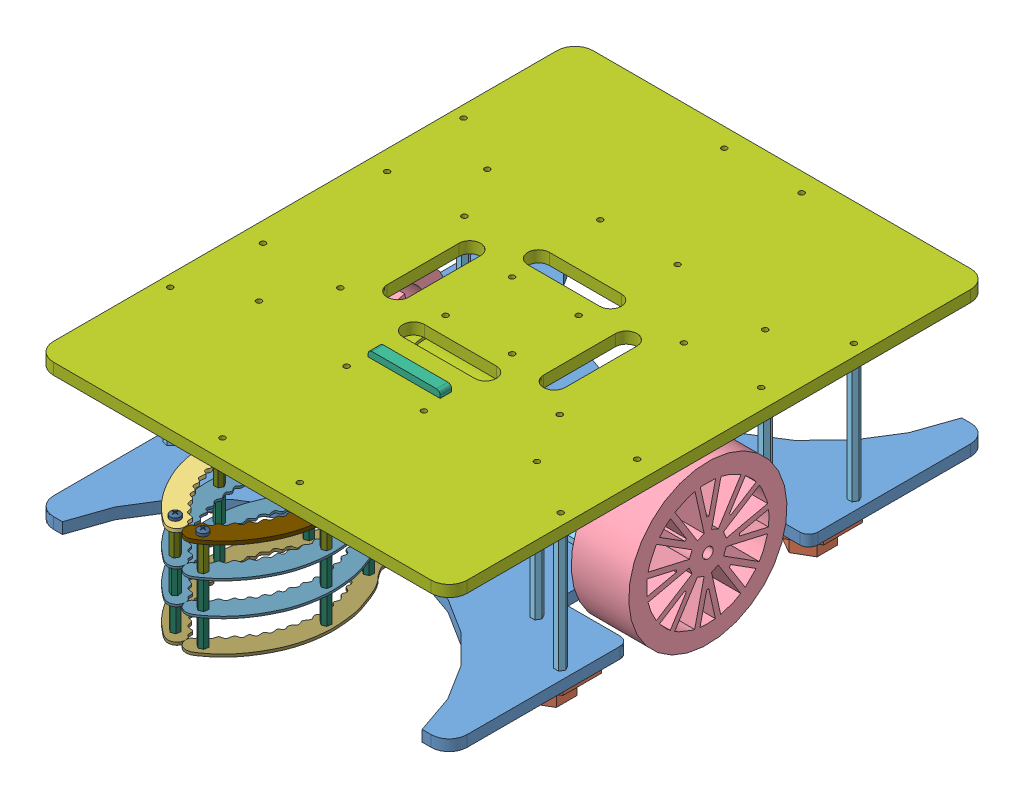
SolidWorks assembly 小车2.0(First Review), configuration Default. Lengths in mm.
Overall size (314.63 161.96 343.93).
98 component instances, 25 part files, 63 mates.
Components (placement in the parent):
- Final Project底板-1: Final Project底板 [Default] at (93.3392 132.9581 90.5224) size (230 6.18 300)
- 滚珠-1: 滚珠 [Default] at (103.3123 152.3308 292.8973) x (0 0 -1) z (0 -1 0) size (43.11 37.34 23.7)
  - 滚珠安装架-1: 滚珠安装架 [Default] at (13.0967 20.7229 19.3727) size (43.11 37.34 17.78)
  - 滚珠球-1: 滚珠球 [Default] at (13.0967 20.7229 37.7877) x (0.980181 0.176565 -0.08983) z (0.185914 -0.976466 0.109313) size (8.89 8.89 8.89)
- 滚珠-2: 滚珠 [Default] at (102.3317 152.3308 123.4025) x (0.866025 0 -0.5) z (0 -1 0) size (43.11 37.34 23.7)
  - 滚珠安装架-1: 滚珠安装架 [Default] at (13.0967 20.7229 19.3727) size (43.11 37.34 17.78)
  - 滚珠球-1: 滚珠球 [Default] at (13.0967 20.7229 37.7877) x (0.980181 0.176565 -0.08983) z (0.185914 -0.976466 0.109313) size (8.89 8.89 8.89)
- 滚珠-3: 滚珠 [Default] at (289.0923 152.3308 147.8973) x (0 0 -1) z (0 -1 0) size (43.11 37.34 23.7)
  - 滚珠安装架-1: 滚珠安装架 [Default] at (13.0967 20.7229 19.3727) size (43.11 37.34 17.78)
  - 滚珠球-1: 滚珠球 [Default] at (13.0967 20.7229 37.7877) x (0.980181 0.176565 -0.08983) z (0.185914 -0.976466 0.109313) size (8.89 8.89 8.89)
- 滚珠-4: 滚珠 [Default] at (288.1117 152.3308 268.4025) x (0.866025 0 -0.5) z (0 -1 0) size (43.11 37.34 23.7)
  - 滚珠安装架-1: 滚珠安装架 [Default] at (13.0967 20.7229 19.3727) size (43.11 37.34 17.78)
  - 滚珠球-1: 滚珠球 [Default] at (13.0967 20.7229 37.7877) x (0.980181 0.176565 -0.08983) z (0.185914 -0.976466 0.109313) size (8.89 8.89 8.89)
- Motor to Wheel-1: Motor to Wheel [Default] at (328.9008 -32.1069 184.0203) x (0.155875 -0.109432 -0.981696) z (0.856774 0.509569 0.079237) size (127.19 130.48 130.09)
  - Wheel-1: Wheel [Default] at (-48.6444 171.6674 66.3367) x (0.769981 -0.482848 -0.417117) z (0.155875 -0.491571 0.856774) size (88 88 32)
  - Motor Mount-1: Motor Mount [Default] at (-46.2771 169.9687 66.283) x (-0.981696 -0.173188 0.079237) z (-0.155875 0.491571 -0.856774) size (38 27 30)
  - DShaftAdaptor_FinalProject-1: DShaftAdaptor_FinalProject [默认] at (-47.3974 167.7348 73.1909) x (0.357457 -0.780517 -0.512852) z (-0.92083 -0.3862 -0.054052) size (12 18.01 13.86)
  - DC_FinalProject-1: DC_FinalProject [默认] at (-61.014 214.2892 6.2529) x (0.981685 0.173278 -0.079184) z (0.109535 -0.853424 -0.509577) size (37 94.36 37)
- Motor to Wheel-2: Motor to Wheel [Default] at (104.9496 -32.1069 230.581) x (-0.155875 -0.109432 0.981696) z (-0.856774 0.509569 -0.079237) size (127.19 130.48 130.09)
  - Wheel-1: Wheel [Default] at (-48.6444 171.6674 66.3367) x (0.769981 -0.482848 -0.417117) z (0.155875 -0.491571 0.856774) size (88 88 32)
  - Motor Mount-1: Motor Mount [Default] at (-46.2771 169.9687 66.283) x (-0.981696 -0.173188 0.079237) z (-0.155875 0.491571 -0.856774) size (38 27 30)
  - DShaftAdaptor_FinalProject-1: DShaftAdaptor_FinalProject [默认] at (-47.3974 167.7348 73.1909) x (0.357457 -0.780517 -0.512852) z (-0.92083 -0.3862 -0.054052) size (12 18.01 13.86)
  - DC_FinalProject-1: DC_FinalProject [默认] at (-61.014 214.2892 6.2529) x (0.981685 0.173278 -0.079184) z (0.109535 -0.853424 -0.509577) size (37 94.36 37)
- CLAW-1: CLAW [默认] at (273.9252 167.8265 279.8987) x (0 -1 0) z (-1 0 0) size (68 134.79 94.66)
  - 支架1-1: 支架1 [默认] at (-30.3115 13.402 28.5) size (50 26 57)
  - M3X11双通铜柱-1: M3X11双通铜柱 [默认] at (-17.3115 9.067 31.75) x (0 0 1) z (-1 0 0) size (5 4.33 11)
  - GB818-M3X6-ZN-4.8-1: GB818-M3X6-ZN-4.8 [默认] at (-24.3115 6.902 33) x (0 0 1) z (-1 0 0) size (5.68 5.86 8.4)
  - M3X11双通铜柱-2: M3X11双通铜柱 [默认] at (-17.3115 -0.933 31.75) x (0 0 1) z (-1 0 0) size (5 4.33 11)
  - GB818-M3X6-ZN-4.8-2: GB818-M3X6-ZN-4.8 [默认] at (-24.3115 -3.098 33) x (0 0 1) z (-1 0 0) size (5.68 5.86 8.4)
  - M3X11双通铜柱-3: M3X11双通铜柱 [默认] at (-17.3115 9.067 79.75) x (0 0 1) z (-1 0 0) size (5 4.33 11)
  - M3X11双通铜柱-4: M3X11双通铜柱 [默认] at (-17.3115 -0.933 79.75) x (0 0 1) z (-1 0 0) size (5 4.33 11)
  - GB818-M3X6-ZN-4.8-3: GB818-M3X6-ZN-4.8 [默认] at (-24.3115 -3.098 81) x (0 0 1) z (-1 0 0) size (5.68 5.86 8.4)
  - GB818-M3X6-ZN-4.8-4: GB818-M3X6-ZN-4.8 [默认] at (-24.3115 6.902 81) x (0 0 1) z (-1 0 0) size (5.68 5.86 8.4)
  - GB818-M3X10-ZN-4.8-1: GB818-M3X10-ZN-4.8 [默认] at (27.6885 1.902 43) x (0 0 1) z (-1 0 0) size (5.68 5.86 12.4)
  - 底部长支架-1: 底部长支架 [默认] at (19.6885 2.0479 43.1669) x (0 -0.990726 -0.135879) z (1 0 0) size (118.75 37.12 1.5)
  - GB6170-M3（自锁）-1: GB6170-M3（自锁） [默认] at (23.5885 1.902 43) x (0 0.843024 -0.537877) z (1 0 0) size (5.54 6.35 3.9)
  - 底部长支架-2: 底部长支架 [默认] at (21.1885 2.0535 66.8382) x (0 -0.994786 0.101989) z (-1 0 0) size (118.75 37.12 1.5)
  - GB818-M3X10-ZN-4.8-2: GB818-M3X10-ZN-4.8 [默认] at (27.6885 1.902 67) x (0 0.048732 -0.998812) z (-1 0 0) size (5.68 5.86 12.4)
  - GB6170-M3（自锁）-2: GB6170-M3（自锁） [默认] at (23.5885 1.902 67) x (0 0.843024 -0.537877) z (1 0 0) size (5.54 6.35 3.9)
  - 装配体3-1: 装配体3 [默认] at (15.0497 28.6742 176.351) x (0 -0.994786 0.101989) z (0 -0.101989 -0.994786) size (98.03 52.4 32.23)
    - 短支架-1: 短支架 [默认] at (-8.1796 12.3612 103.8864) size (98.03 1.2 32.23)
    - M3X17+6铜柱-1: M3X17+6铜柱 [默认] at (-9.1857 -4.6388 105.7687) x (-0.247063 0 -0.969) z (0 1 0) size (5 4.33 23)
    - M3X17+6铜柱-2: M3X17+6铜柱 [默认] at (-43.3235 -4.6388 88.3304) x (-0.247063 0 -0.969) z (0 1 0) size (5 4.33 23)
    - M3X17+6铜柱-3: M3X17+6铜柱 [默认] at (-91.3824 -4.6388 105.0913) x (-0.247063 0 -0.969) z (0 1 0) size (5 4.33 23)
    - M3X17+6铜柱-4: M3X17+6铜柱 [默认] at (-42.7844 13.5612 84.4192) x (1 0 0) z (0 1 0) size (5 4.33 23)
    - M3X17+6铜柱-5: M3X17+6铜柱 [默认] at (-8.6466 13.5612 101.8575) x (1 0 0) z (0 1 0) size (5 4.33 23)
    - M3X17+6铜柱-6: M3X17+6铜柱 [默认] at (-90.8433 13.5612 101.1801) x (1 0 0) z (0 1 0) size (5 4.33 23)
    - 短支架-2: 短支架 [默认] at (-8.1796 30.5612 103.8864) size (98.03 1.2 32.23)
    - M3X16双通铜柱-1: M3X16双通铜柱 [默认] at (-87.3627 47.7612 102.2163) x (-0.837169 0 -0.546944) z (0 -1 0) size (5 4.33 16)
    - M3X16双通铜柱-2: M3X16双通铜柱 [默认] at (-39.3038 47.7612 85.4554) x (-0.837169 0 -0.546944) z (0 -1 0) size (5 4.33 16)
    - M3X16双通铜柱-3: M3X16双通铜柱 [默认] at (-5.1659 47.7612 102.8937) x (-0.837169 0 -0.546944) z (0 -1 0) size (5 4.33 16)
  - GB818-M3X6-ZN-4.8-5: GB818-M3X6-ZN-4.8 [默认] at (15.1885 61.1614 85.9822) x (0 0 -1) z (1 0 0) size (5.68 5.86 8.4)
  - GB818-M3X6-ZN-4.8-6: GB818-M3X6-ZN-4.8 [默认] at (15.1885 107.2603 64.4072) x (0 0 -1) z (1 0 0) size (5.68 5.86 8.4)
  - GB818-M3X6-ZN-4.8-7: GB818-M3X6-ZN-4.8 [默认] at (15.1885 25.4231 72.1164) x (0 0 -1) z (1 0 0) size (5.68 5.86 8.4)
  - 装配体4-1: 装配体4 [默认] at (-2.8438 34.6565 -65.0628) x (0 -0.990726 -0.135879) z (0 -0.135879 0.990726) size (98.03 52.4 32.23)
    - 短支架-1: 短支架 [默认] at (-5.8923 4.3323 103.8864) size (98.03 1.2 32.23)
    - M3X17+6铜柱-1: M3X17+6铜柱 [默认] at (-88.556 22.5323 105.5102) x (1 0 0) z (0 -1 0) size (5 4.33 23)
    - M3X16双通铜柱-1: M3X16双通铜柱 [默认] at (-40.4971 -29.8677 84.4192) x (1 0 0) z (0 1 0) size (5 4.33 16)
    - M3X17+6铜柱-2: M3X17+6铜柱 [默认] at (-40.4971 22.5323 88.7493) x (1 0 0) z (0 -1 0) size (5 4.33 23)
    - M3X17+6铜柱-3: M3X17+6铜柱 [默认] at (-6.3593 22.5323 106.1877) x (1 0 0) z (0 -1 0) size (5 4.33 23)
    - M3X17+6铜柱-4: M3X17+6铜柱 [默认] at (-6.3593 4.3323 106.1877) x (1 0 0) z (0 -1 0) size (5 4.33 23)
    - M3X17+6铜柱-5: M3X17+6铜柱 [默认] at (-40.4971 4.3323 88.7493) x (1 0 0) z (0 -1 0) size (5 4.33 23)
    - M3X17+6铜柱-6: M3X17+6铜柱 [默认] at (-88.556 4.3323 105.5102) x (1 0 0) z (0 -1 0) size (5 4.33 23)
    - 短支架-2: 短支架 [默认] at (-5.8923 -13.8677 103.8864) size (98.03 1.2 32.23)
    - M3X16双通铜柱-2: M3X16双通铜柱 [默认] at (-88.556 -29.8677 101.1801) x (1 0 0) z (0 1 0) size (5 4.33 16)
    - M3X16双通铜柱-3: M3X16双通铜柱 [默认] at (-6.3593 -29.8677 101.8575) x (1 0 0) z (0 1 0) size (5 4.33 16)
  - GB818-M3X6-ZN-4.8-8: GB818-M3X6-ZN-4.8 [默认] at (15.1885 25.584 38.6892) x (0 0 -1) z (1 0 0) size (5.68 5.86 8.4)
  - GB818-M3X6-ZN-4.8-9: GB818-M3X6-ZN-4.8 [默认] at (15.1885 61.7747 26.0512) x (0 0 -1) z (1 0 0) size (5.68 5.86 8.4)
  - GB818-M3X6-ZN-4.8-10: GB818-M3X6-ZN-4.8 [默认] at (15.1885 107.1104 49.1869) x (0 0 -1) z (1 0 0) size (5.68 5.86 8.4)
  - GB818-M3X12-ZN-4.8-1: GB818-M3X12-ZN-4.8 [默认] at (-40.3115 1.902 43) x (0 0 -1) z (1 0 0) size (5.68 5.86 14.4)
  - 左边长支架-1: 左边长支架 [默认] at (-34.7115 1.9971 43.5105) x (0 -0.990726 -0.135879) z (0 -0.135879 0.990726) size (129.58 2 47.14)
  - GB6170-M3（自锁）-3: GB6170-M3（自锁） [默认] at (-37.1115 1.902 43) x (0 0 1) z (-1 0 0) size (5.54 6.35 3.9)
  - GB818-M3X6-ZN-4.8-11: GB818-M3X6-ZN-4.8 [默认] at (-28.7115 25.584 38.6892) x (0 0 1) z (-1 0 0) size (5.68 5.86 8.4)
  - GB818-M3X6-ZN-4.8-12: GB818-M3X6-ZN-4.8 [默认] at (-28.7115 61.7747 26.0512) x (0 0 1) z (-1 0 0) size (5.68 5.86 8.4)
  - GB818-M3X6-ZN-4.8-13: GB818-M3X6-ZN-4.8 [默认] at (-28.7115 107.1104 49.1869) x (0 0 1) z (-1 0 0) size (5.68 5.86 8.4)
  - 小舵机-1: 小舵机 [默认] at (-25.3115 1.902 77) x (0 0 -1) z (0 1 0) size (57.5 45 20)
  - GB818-M3X6-ZN-4.8-14: GB818-M3X6-ZN-4.8 [默认] at (-20.3115 -3.098 81) x (0 0 -1) z (1 0 0) size (5.68 5.86 8.4)
  - GB818-M3X6-ZN-4.8-15: GB818-M3X6-ZN-4.8 [默认] at (-20.3115 6.902 81) x (0 0 -1) z (1 0 0) size (5.68 5.86 8.4)
  - GB818-M3X6-ZN-4.8-16: GB818-M3X6-ZN-4.8 [默认] at (-20.3115 6.902 33) x (0 0 -1) z (1 0 0) size (5.68 5.86 8.4)
  - GB818-M3X6-ZN-4.8-17: GB818-M3X6-ZN-4.8 [默认] at (-20.3115 -3.098 33) x (0 0 -1) z (1 0 0) size (5.68 5.86 8.4)
  - 金属主舵盘-1: 金属主舵盘 [默认] at (-32.7115 1.902 67) x (0 0.544938 -0.838476) z (0 -0.838476 -0.544938) size (20 4.5 20)
  - 右边长支架-1: 右边长支架 [默认] at (-32.7115 2.0165 67.0256) x (0 -0.994786 0.101989) z (0 -0.101989 -0.994786) size (129.29 2 48.17)
  - GB818-M3X6-ZN-4.8-18: GB818-M3X6-ZN-4.8 [默认] at (-28.7115 107.2603 64.4072) x (0 0 1) z (-1 0 0) size (5.68 5.86 8.4)
  - GB818-M3X6-ZN-4.8-19: GB818-M3X6-ZN-4.8 [默认] at (-28.7115 61.1614 85.9822) x (0 0 1) z (-1 0 0) size (5.68 5.86 8.4)
  - GB818-M3X6-ZN-4.8-20: GB818-M3X6-ZN-4.8 [默认] at (-28.7115 25.4231 72.1164) x (0 0 1) z (-1 0 0) size (5.68 5.86 8.4)
  - GB818-M3X6-ZN-4.8-21: GB818-M3X6-ZN-4.8 [默认] at (-26.7115 1.902 67) x (0 0 1) z (-1 0 0) size (5.68 5.86 8.4)
  - GB818-M3X5-ZN-4.8-1: GB818-M3X5-ZN-4.8 [默认] at (-29.7115 1.5867 73.9644) x (0 0 1) z (-1 0 0) size (5.68 5.86 7.4)
  - GB818-M3X5-ZN-4.8-2: GB818-M3X5-ZN-4.8 [默认] at (-29.7115 2.0134 60.0146) x (0 0 1) z (-1 0 0) size (5.68 5.86 7.4)
- erSupport-1: erSupport [Default] at (108.3973 139.1381 288.8292) x (0.976523 0 0.215415) z (-0.215415 0 0.976523) size (5.77 68 5)
- erSupport-2: erSupport [Default] at (139.6731 139.1381 270.7721) size (5.77 68 5)
- erSupport-3: erSupport [Default] at (294.1773 139.1381 270.7721) size (5.77 68 5)
- erSupport-4: erSupport [Default] at (325.4531 139.1381 288.8292) size (5.77 68 5)
- erSupport-5: erSupport [Default] at (294.1773 139.1381 143.8292) size (5.77 68 5)
- erSupport-6: erSupport [Default] at (325.4531 139.1381 125.7721) size (5.77 68 5)
- erSupport-7: erSupport [Default] at (108.3973 139.1381 125.7721) size (5.77 68 5)
- erSupport-8: erSupport [Default] at (139.6731 139.1381 143.8292) size (5.77 68 5)
- Claw Board-1: Claw Board [Default] at (214.962 164.6549 260.9507) size (80 88 6.35)
- Upper layer-1: Upper layer [Default] at (166.5079 207.1381 123.9809) size (230 6.35 300)
Mates (geometry in assembly coordinates):
- 同心2: concentric aligned: cylinder of Final Project底板-1 through (113.7252 132.9581 219.5507) axis (0 1 0) radius 1.5; cylinder of ? through (113.7252 135.0181 219.5507) axis (0 1 0) radius 1.5
- 重合1: coincident aligned: plane of Final Project底板-1 through (112.2252 132.9581 219.5507) normal (1 0 0); plane of ? through (112.2252 135.0181 224.0507) normal (1 0 0)
- 重合2: coincident anti-aligned: plane of Final Project底板-1 through (93.3392 139.1381 90.5224) normal (0 1 0); plane of ? through (105.3812 139.1381 207.3367) normal (0 -1 0)
- 重合5: coincident anti-aligned: plane of Final Project底板-1 through (93.3392 139.1381 90.5224) normal (0 1 0); plane of ? through (278.4692 139.1381 207.2647) normal (0 -1 0)
- 平行1: parallel anti-aligned: plane of Final Project底板-1 through (93.3392 139.1381 357.3007) normal (0 0 1); plane of ? through (245.4252 194.1381 297.7474) normal (0 0 -1)
- 重合7: coincident anti-aligned: plane of Final Project底板-1 through (93.3392 132.9581 90.5224) normal (0 -1 0); plane of 滚珠-1/滚珠安装架-1 through (124.0352 132.9581 279.8007) normal (0 1 0)
- 重合8: coincident anti-aligned: plane of Final Project底板-1 through (93.3392 132.9581 90.5224) normal (0 -1 0); plane of 滚珠-4/滚珠安装架-1 through (309.8152 132.9581 279.8007) normal (0 1 0)
- 重合9: coincident anti-aligned: plane of Final Project底板-1 through (93.3392 132.9581 90.5224) normal (0 -1 0); plane of 滚珠-3/滚珠安装架-1 through (309.8152 132.9581 134.8007) normal (0 1 0)
- 重合10: coincident anti-aligned: plane of Final Project底板-1 through (93.3392 132.9581 90.5224) normal (0 -1 0); plane of 滚珠-2/滚珠安装架-1 through (124.0352 132.9581 134.8007) normal (0 1 0)
- 重合11: coincident anti-aligned: plane of Final Project底板-1 through (93.3392 139.1381 90.5224) normal (0 1 0); plane of ? through (278.4692 139.1381 207.2647) normal (0 -1 0)
- 同心3: concentric aligned: cylinder of Final Project底板-1 through (270.1252 132.9581 224.0507) axis (0 1 0) radius 1.5; cylinder of ? through (270.1252 135.0181 224.0507) axis (0 1 0) radius 1.5
- 重合13: coincident aligned: plane of Final Project底板-1 through (268.6252 132.9581 219.5507) normal (1 0 0); plane of ? through (268.6252 135.0181 219.5507) normal (1 0 0)
- useless2: distance = 86.5 mm aligned: plane of ? through (245.4252 194.1381 337.7474) normal (1 0 0); plane of Final Project底板-1 through (331.9252 139.1381 90.5224) normal (1 0 0)
- 重合17: coincident anti-aligned: plane of ? through (162.6047 199.1381 381.4187) normal (0 1 0); plane of ? through (93.3392 199.1381 90.5224) normal (0 -1 0)
- 重合18: coincident aligned: plane of Final Project底板-1 through (93.3392 139.1381 357.3007) normal (0 0 1); plane of ? through (93.3392 308.6573 357.3007) normal (0 0 1)
- 重合19: coincident aligned: plane of Final Project底板-1 through (101.9252 139.1381 90.5224) normal (-1 0 0); plane of ? through (101.9252 308.6573 90.5224) normal (-1 0 0)
- 重合20: coincident anti-aligned: plane of Final Project底板-1 through (93.3392 139.1381 90.5224) normal (0 1 0); plane of ? through (279.6383 139.1381 374.6654) normal (0 -1 0)
- 重合21: coincident anti-aligned: plane of Final Project底板-1 through (93.3392 139.1381 90.5224) normal (0 1 0); plane of Motor to Wheel-2/Motor Mount-1 through (141.9252 139.1381 226.3007) normal (0 -1 0)
- 同心12: concentric aligned: cylinder of Final Project底板-1 through (148.4252 132.9581 194.3007) axis (0 1 0) radius 1.5; cylinder of Motor to Wheel-2/Motor Mount-1 through (148.4252 139.1381 194.3007) axis (0 1 0) radius 1.5
- 重合22: coincident aligned: plane of Final Project底板-1 through (146.9252 132.9581 194.3007) normal (1 0 0); plane of Motor to Wheel-2/Motor Mount-1 through (146.9252 139.1381 194.3007) normal (1 0 0)
- 重合23: coincident anti-aligned: plane of Final Project底板-1 through (93.3392 139.1381 90.5224) normal (0 1 0); plane of Motor to Wheel-1/Motor Mount-1 through (291.9252 139.1381 188.3007) normal (0 -1 0)
- 同心13: concentric aligned: cylinder of Final Project底板-1 through (271.4252 132.9581 198.8007) axis (0 1 0) radius 1.5; cylinder of Motor to Wheel-1/Motor Mount-1 through (271.4252 139.1381 198.8007) axis (0 1 0) radius 1.5
- 重合24: coincident aligned: plane of Final Project底板-1 through (269.9252 132.9581 194.3007) normal (1 0 0); plane of Motor to Wheel-1/Motor Mount-1 through (269.9252 139.1381 194.3007) normal (1 0 0)
- 同心14: concentric aligned: cylinder of Final Project底板-1 through (139.6731 139.1381 143.8292) axis (0 -1 0) radius 1.5; cylinder of 滚珠-2/滚珠安装架-1 through (139.6731 132.9581 143.8292) axis (0 -1 0) radius 1.5
- 同心15: concentric aligned: cylinder of Final Project底板-1 through (108.3973 139.1381 125.7721) axis (0 -1 0) radius 1.5; cylinder of 滚珠-2/滚珠安装架-1 through (108.3973 132.9581 125.7721) axis (0 -1 0) radius 1.5
- 同心16: concentric aligned: cylinder of Final Project底板-1 through (139.6731 139.1381 270.7721) axis (0 -1 0) radius 1.5; cylinder of 滚珠-1/滚珠安装架-1 through (139.6731 132.9581 270.7721) axis (0 -1 0) radius 1.5
- 同心17: concentric aligned: cylinder of Final Project底板-1 through (108.3973 139.1381 288.8292) axis (0 -1 0) radius 1.5; cylinder of 滚珠-1/滚珠安装架-1 through (108.3973 132.9581 288.8292) axis (0 -1 0) radius 1.5
- 同心18: concentric aligned: cylinder of Final Project底板-1 through (325.4531 139.1381 288.8292) axis (0 -1 0) radius 1.5; cylinder of 滚珠-4/滚珠安装架-1 through (325.4531 132.9581 288.8292) axis (0 -1 0) radius 1.5
- 同心19: concentric aligned: cylinder of Final Project底板-1 through (294.1773 139.1381 270.7721) axis (0 -1 0) radius 1.5; cylinder of 滚珠-4/滚珠安装架-1 through (294.1773 132.9581 270.7721) axis (0 -1 0) radius 1.5
- 同心20: concentric aligned: cylinder of Final Project底板-1 through (325.4531 139.1381 125.7721) axis (0 -1 0) radius 1.5; cylinder of 滚珠-3/滚珠安装架-1 through (325.4531 132.9581 125.7721) axis (0 -1 0) radius 1.5
- 同心21: concentric aligned: cylinder of Final Project底板-1 through (294.1773 139.1381 143.8292) axis (0 -1 0) radius 1.5; cylinder of 滚珠-3/滚珠安装架-1 through (294.1773 132.9581 143.8292) axis (0 -1 0) radius 1.5
- 重合26: coincident aligned: plane of Final Project底板-1 through (236.9252 139.1381 267.3007) normal (0 0 -1); plane of CLAW-1/支架1-1 through (188.4252 198.1381 267.3007) normal (0 0 -1)
- 平行2: parallel anti-aligned: plane of Final Project底板-1 through (93.3392 139.1381 90.5224) normal (0 1 0); plane of CLAW-1/支架1-1 through (188.4252 148.1381 267.3007) normal (0 -1 0)
- 同心22: concentric aligned: cylinder of CLAW-1/支架1-1 through (216.9252 173.1381 259.3007) axis (0 0 1) radius 3; cylinder of Claw Board-1 through (216.9252 173.1381 260.9507) axis (0 0 1) radius 3
- 重合27: coincident anti-aligned: plane of CLAW-1/支架1-1 through (188.4252 198.1381 267.3007) normal (0 0 -1); plane of Claw Board-1 through (244.9252 141.1381 267.3007) normal (0 0 1)
- 同心23: concentric aligned: cylinder of CLAW-1/支架1-1 through (209.9252 173.1381 259.3007) axis (0 0 1) radius 1.5; cylinder of Claw Board-1 through (209.9252 173.1381 260.9507) axis (0 0 1) radius 1.5
- 同心24: concentric aligned: cylinder of CLAW-1/支架1-1 through (216.9252 180.1381 259.3007) axis (0 0 1) radius 1.5; cylinder of Claw Board-1 through (216.9252 180.1381 260.9507) axis (0 0 1) radius 1.5
- 同心25: concentric aligned: cylinder of CLAW-1/支架1-1 through (223.9252 173.1381 259.3007) axis (0 0 1) radius 1.5; cylinder of Claw Board-1 through (223.9252 173.1381 260.9507) axis (0 0 1) radius 1.5
- 同心26: concentric aligned: cylinder of CLAW-1/支架1-1 through (216.9252 166.1381 259.3007) axis (0 0 1) radius 1.5; cylinder of Claw Board-1 through (216.9252 166.1381 260.9507) axis (0 0 1) radius 1.5
- 同心27: concentric anti-aligned: cylinder of Final Project底板-1 through (108.3973 139.1381 288.8292) axis (0 -1 0) radius 1.5; cylinder of erSupport-1 through (108.3973 139.1381 288.8292) axis (0 1 0) radius 1.5
- 同心28: concentric anti-aligned: cylinder of Final Project底板-1 through (139.6731 139.1381 270.7721) axis (0 -1 0) radius 1.5; cylinder of erSupport-2 through (139.6731 139.1381 270.7721) axis (0 1 0) radius 1.5
- 重合28: coincident anti-aligned: plane of Final Project底板-1 through (93.3392 139.1381 90.5224) normal (0 1 0); plane of erSupport-1 through (108.3973 139.1381 288.8292) normal (0 -1 0)
- 重合29: coincident anti-aligned: plane of Final Project底板-1 through (93.3392 139.1381 90.5224) normal (0 1 0); plane of erSupport-2 through (139.6731 139.1381 270.7721) normal (0 -1 0)
- 重合30: coincident anti-aligned: plane of Final Project底板-1 through (93.3392 139.1381 90.5224) normal (0 1 0); plane of erSupport-3 through (294.1773 139.1381 270.7721) normal (0 -1 0)
- 重合31: coincident anti-aligned: plane of Final Project底板-1 through (93.3392 139.1381 90.5224) normal (0 1 0); plane of erSupport-4 through (325.4531 139.1381 288.8292) normal (0 -1 0)
- 同心29: concentric anti-aligned: cylinder of Final Project底板-1 through (325.4531 139.1381 288.8292) axis (0 -1 0) radius 1.5; cylinder of erSupport-4 through (325.4531 139.1381 288.8292) axis (0 1 0) radius 1.5
- 同心30: concentric anti-aligned: cylinder of Final Project底板-1 through (294.1773 139.1381 270.7721) axis (0 -1 0) radius 1.5; cylinder of erSupport-3 through (294.1773 139.1381 270.7721) axis (0 1 0) radius 1.5
- 重合32: coincident anti-aligned: plane of Final Project底板-1 through (93.3392 139.1381 90.5224) normal (0 1 0); plane of erSupport-5 through (294.1773 139.1381 143.8292) normal (0 -1 0)
- 重合33: coincident anti-aligned: plane of Final Project底板-1 through (93.3392 139.1381 90.5224) normal (0 1 0); plane of erSupport-6 through (325.4531 139.1381 125.7721) normal (0 -1 0)
- 同心31: concentric anti-aligned: cylinder of Final Project底板-1 through (294.1773 139.1381 143.8292) axis (0 -1 0) radius 1.5; cylinder of erSupport-5 through (294.1773 139.1381 143.8292) axis (0 1 0) radius 1.5
- 同心32: concentric anti-aligned: cylinder of Final Project底板-1 through (325.4531 139.1381 125.7721) axis (0 -1 0) radius 1.5; cylinder of erSupport-6 through (325.4531 139.1381 125.7721) axis (0 1 0) radius 1.5
- 重合34: coincident anti-aligned: plane of Final Project底板-1 through (93.3392 139.1381 90.5224) normal (0 1 0); plane of erSupport-7 through (108.3973 139.1381 125.7721) normal (0 -1 0)
- 重合35: coincident anti-aligned: plane of Final Project底板-1 through (93.3392 139.1381 90.5224) normal (0 1 0); plane of erSupport-8 through (139.6731 139.1381 143.8292) normal (0 -1 0)
- 同心33: concentric anti-aligned: cylinder of Final Project底板-1 through (108.3973 139.1381 125.7721) axis (0 -1 0) radius 1.5; cylinder of erSupport-7 through (108.3973 139.1381 125.7721) axis (0 1 0) radius 1.5
- 同心34: concentric anti-aligned: cylinder of Final Project底板-1 through (139.6731 139.1381 143.8292) axis (0 -1 0) radius 1.5; cylinder of erSupport-8 through (139.6731 139.1381 143.8292) axis (0 1 0) radius 1.5
- 重合36: coincident anti-aligned: plane of ? through (236.9252 213.3181 267.3007) normal (0 0 -1); plane of Claw Board-1 through (244.9252 141.1381 267.3007) normal (0 0 1)
- 重合37: coincident anti-aligned: plane of ? through (236.9252 213.3181 261.3007) normal (-1 0 0); plane of Claw Board-1 through (236.9252 209.1381 267.3007) normal (1 0 0)
- 重合38: coincident anti-aligned: plane of ? through (196.9252 213.3181 267.3007) normal (1 0 0); plane of Claw Board-1 through (196.9252 215.1381 267.3007) normal (-1 0 0)
- 重合39: coincident anti-aligned: plane of ? through (93.3392 207.1381 90.5224) normal (0 -1 0); plane of Claw Board-1 through (244.9252 207.1381 267.3007) normal (0 1 0)
- 重合40: coincident anti-aligned: plane of Final Project底板-1 through (93.3392 139.1381 90.5224) normal (0 1 0); plane of Claw Board-1 through (188.9252 139.1381 267.3007) normal (0 -1 0)
- 同心35: concentric aligned: cylinder of erSupport-6 through (325.4531 139.1381 125.7721) axis (0 1 0) radius 1.5; cylinder of Upper layer-1 through (325.4531 207.1381 125.7721) axis (0 1 0) radius 1.5
- 重合41: coincident anti-aligned: plane of erSupport-6 through (325.4531 207.1381 125.7721) normal (0 1 0); plane of Upper layer-1 through (317.8947 207.1381 347.2013) normal (0 -1 0)
- 平行5: parallel aligned: plane of Final Project底板-1 through (331.9252 139.1381 90.5224) normal (1 0 0); plane of Upper layer-1 through (331.9231 213.4881 347.3021) normal (1 0 0)
